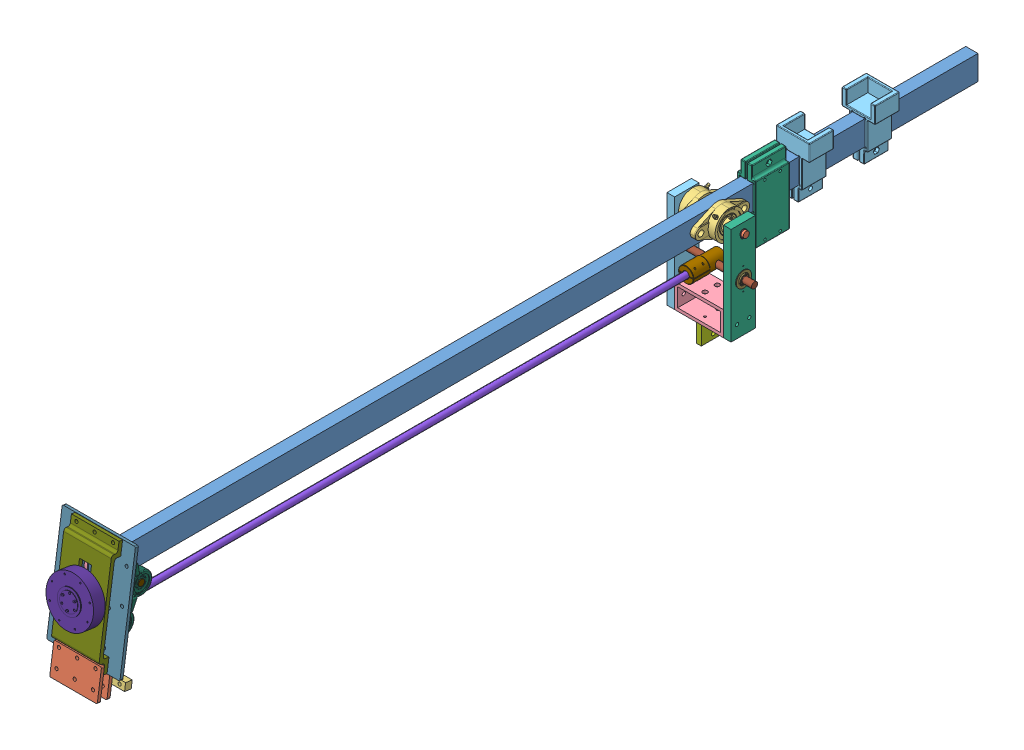
SolidWorks assembly BoomAssembly, configuration Unmovable Boom. Lengths in mm.
Overall size (166.47 305.68 1906.59).
39 component instances, 24 part files, 44 mates.
Components (placement in the parent):
- Boom-1: Boom [Default] at (0 158.75 -542.925) size (25.4 50.8 1828.8)
- Boom_Yoke Shaft-1: Boom_Yoke Shaft [Default] at (66.675 158.75 0) x (0 0 -1) z (1 0 0) size (12.7 12.7 130.18)
- UCFL201-8-TheTimkenCompany-3D-09-18-2023 (1).stp-1: UCFL201-8-TheTimkenCompany-3D-09-18-2023 (1).stp [Default] at (-12.7 158.75 0) x (0 0 1) z (0 1 0) size (113 33.3 60)
- UCFL201-8-TheTimkenCompany-3D-09-18-2023 (1).stp-2: UCFL201-8-TheTimkenCompany-3D-09-18-2023 (1).stp [Default] at (12.7 158.75 0) x (0 0 -1) z (0 1 0) size (113 33.3 60)
- Yoke-1: Yoke [Default] at origin size (133.35 241.3 50.8)
  - Yoke_Base-1: Yoke_Base [Default] x (0 0 -1) z (1 0 0) size (50.8 50.8 101.6)
  - Yoke-Prong-1: Yoke-Prong [Default] at (-50.8 0 0) x (0 0 1) z (-1 0 0) size (50.8 203.2 15.88)
  - Yoke_Prong_Encoder Side-1: Yoke_Prong_Encoder Side [Default] at (50.8 0 0) x (0 0 -1) z (1 0 0) size (50.8 203.2 15.88)
  - Yoke_Base Mount-1: Yoke_Base Mount [Default] at (0 -25.4 0) x (0 0 1) z (0 -1 0) size (50.8 9.53 38.1)
- 00_03_Boom_Assembly-1: 00_03_Boom_Assembly [Default] at (0 77.032 1256.8235) x (1 0 0) z (0 -0.000662 -1) size (160.07 31.75 1303.92)
  - 00_03_01_Boom-1: 00_03_01_Boom [Default] at origin size (12.7 12.7 1244.6)
  - 00_03_02_Boom_Shaft_End-1: 00_03_02_Boom_Shaft_End [3463N51] at (0 0 5.5563) size (31.71 31.75 69.85)
  - 00_03_02_Boom_Shaft_End-2: 00_03_02_Boom_Shaft_End [3463N51] at (0 0 1239.0438) x (-1 0 0) z (0 0 -1) size (31.71 31.75 69.85)
  - 00_03_03_92313A576_Super-Corrosion-Resistant Cup-Point Set Screw-1: 00_03_03_92313A576_Super-Corrosion-Resistant Cup-Point Set Screw [92313A576] at (0 0 -25.2586) x (-1 0 0) z (0 0 -1) size (8.13 8.07 10.1)
  - 00_03_03_92313A576_Super-Corrosion-Resistant Cup-Point Set Screw-2: 00_03_03_92313A576_Super-Corrosion-Resistant Cup-Point Set Screw [92313A576] at (0 0 1255.8886) size (8.13 8.07 10.1)
  - Rod-Yoke Shaft-1: Rod-Yoke Shaft [Default] at (0 0 1256.8238) size (160.07 12.7 12.7)
- 6383K234_Ball Bearing-1: 6383K234_Ball Bearing [6383K234] at (63.4365 76.2 0) x (0 0 1) z (-1 0 0) size (31.75 31.75 11.13)
- 6383K234_Ball Bearing-2: 6383K234_Ball Bearing [6383K234] at (-63.4365 76.2 0) x (0 0 -1) z (1 0 0) size (31.75 31.75 11.13)
- 90030A101_Heavy Duty External Retaining Ring-1: 90030A101_Heavy Duty External Retaining Ring [90030A101] at (67.425 158.75 0) x (0 0 -1) z (1 0 0) size (13.48 16.2 1.5)
- 90030A101_Heavy Duty External Retaining Ring-2: 90030A101_Heavy Duty External Retaining Ring [90030A101] at (70.5492 76.2 0) x (0 -0.10728 -0.994229) z (1 0 0) size (13.48 16.2 1.5) (hidden)
- Knuckle-1: Knuckle [Default] at (0 161.9092 1279.2741) x (0 0.142304 0.989823) z (-1 0 0) size (107.06 275.35 152.4)
  - Knuckle Plate^Knuckle-1: Knuckle Plate^Knuckle [Default] at origin size (6.35 228.6 152.4) (virtual)
  - 5913K61_Low-Profile Mounted Sealed Steel Ball Bearing-1: 5913K61_Low-Profile Mounted Sealed Steel Ball Bearing [5913K61] at (-22.2 0 -63.5) x (0 1 0) z (0 0 1) size (86.1 44.81 28.6)
  - 5913K61_Low-Profile Mounted Sealed Steel Ball Bearing-3: 5913K61_Low-Profile Mounted Sealed Steel Ball Bearing [5913K61] at (-22.2 0 63.5) x (0 -1 0) z (0 0 -1) size (86.1 44.81 28.6)
  - 5913K61_Low-Profile Mounted Sealed Steel Ball Bearing-4: 5913K61_Low-Profile Mounted Sealed Steel Ball Bearing [5913K61] at (-22.2 -82.55 -38.1) x (0 1 0) z (0 0 1) size (86.1 44.81 28.6)
  - 5913K61_Low-Profile Mounted Sealed Steel Ball Bearing-6: 5913K61_Low-Profile Mounted Sealed Steel Ball Bearing [5913K61] at (-22.2 -82.55 38.1) x (0 -1 0) z (0 0 -1) size (86.1 44.81 28.6)
  - 00_04_01_CANSide mount-1: 00_04_01_CANSide mount [Default] at (19.05 -127 0) x (-1 0 0) z (0 0 -1) size (20.32 227.33 99.06)
  - CE_AK80-6_Model-1: CE_AK80-6_Model [AliExpress (2.5mm)] at (26.67 -41.275 0) x (0 -1 0) z (0 0 1) size (98 40.5 98)
  - Boom_Knuckle Shaft-1: Boom_Knuckle Shaft [Default] at (-22.2 0 0) x (0 0 -1) z (1 0 0) size (142.17 12.7 12.7)
  - Rod_Knuckle Shaft-1: Rod_Knuckle Shaft [Default] at (-22.2 -82.55 0) x (0 0 -1) z (-1 0 0) size (94.55 12.7 12.7)
  - Bumper^Knuckle-1: Bumper^Knuckle [Default] at (0 -147.32 0) x (0 0 1) z (-1 0 0) size (99.06 62.94 6.35) (virtual)
  - Bumper^Knuckle-4: Bumper^Knuckle [Default] at (13.97 -147.32 0) x (0 0 -1) z (1 0 0) size (99.06 62.94 6.35) (virtual)
  - Part2^Knuckle-1: Part2^Knuckle [Default] at (-36.9201 -192.3946 0) x (0 0 -1) z (0 1 0) size (99.06 13.97 15.24) (virtual)
- 1870K3_Easy-Access Flange-Mounted Shaft Support-1: 1870K3_Easy-Access Flange-Mounted Shaft Support [1870K3] at (38.1 158.75 1257.3) x (0 -0.707107 -0.707107) z (0 0.707107 -0.707107) size (57.15 25.4 57.15)
- 1870K3_Easy-Access Flange-Mounted Shaft Support-2: 1870K3_Easy-Access Flange-Mounted Shaft Support [1870K3] at (-38.1 158.75 1257.3) x (0 0.707107 0.707107) z (0 0.707107 -0.707107) size (57.15 25.4 57.15)
- Battery Holder-1: Battery Holder [Default] at (0.127 184.15 -263.525) x (-1 0 0) z (0 0 -1) size (69.05 117.15 187.7)
  - Part1^Battery Holder adjustable-4: Part1^Battery Holder adjustable [Default] at (0 0 -93.85) size (69.05 117.15 50.8)
  - Part1^Battery Holder adjustable-3: Part1^Battery Holder adjustable [Default] at (0 0 93.85) x (-1 0 0) z (0 0 -1) size (69.05 117.15 50.8)
- PCB Holder-1: PCB Holder [Default] at (0 133.35 -144.3258) x (-1 0 0) z (0 0 1) size (38.35 146.05 71.16)
Mates (geometry in assembly coordinates):
- Concentric2: concentric anti-aligned: cylinder of Boom_Yoke Shaft-1 through (73.025 158.75 0) axis (-1 0 0) radius 6.35; cylinder of UCFL201-8-TheTimkenCompany-3D-09-18-2023 (1).stp-1 through (-30.5 158.75 0) axis (1 0 0) radius 6.35
- Concentric5: concentric aligned: cylinder of Boom_Yoke Shaft-1 through (73.025 158.75 0) axis (-1 0 0) radius 6.35; cylinder of UCFL201-8-TheTimkenCompany-3D-09-18-2023 (1).stp-2 through (30.5 158.75 0) axis (-1 0 0) radius 6.35
- Coincident7: coincident anti-aligned: plane of Boom-1 through (-12.7 133.35 1285.875) normal (-1 0 0); plane of UCFL201-8-TheTimkenCompany-3D-09-18-2023 (1).stp-1 through (-12.7 158.75 -0.033) normal (1 0 0)
- Coincident8: coincident anti-aligned: plane of Boom-1 through (12.7 133.35 1285.875) normal (1 0 0); plane of UCFL201-8-TheTimkenCompany-3D-09-18-2023 (1).stp-2 through (12.7 158.75 0.033) normal (-1 0 0)
- Coincident10: coincident aligned: plane of Boom-1 through (0 158.75 -542.925) normal (0 1 0); plane of UCFL201-8-TheTimkenCompany-3D-09-18-2023 (1).stp-1 through (-12.7 158.75 0) normal (0 1 0)
- Coincident11: coincident aligned: plane of Boom-1 through (0 158.75 -542.925) normal (0 1 0); plane of UCFL201-8-TheTimkenCompany-3D-09-18-2023 (1).stp-2 through (12.7 158.75 0) normal (0 1 0)
- Concentric6: concentric anti-aligned: cylinder of Yoke-1/Yoke-Prong-1 through (-66.675 76.2 0) axis (1 0 0) radius 6.35; cylinder of 00_03_Boom_Assembly-1/Rod-Yoke Shaft-1 through (69.7992 76.2 0) axis (-1 0 0) radius 6.35
- Coincident15: coincident anti-aligned: plane of Boom-1 through (0 158.75 -542.925) normal (1 0 0); plane of 00_03_Boom_Assembly-1/00_03_02_Boom_Shaft_End-2 through (0 76.2118 17.78) normal (-1 0 0)
- Coincident16: coincident anti-aligned: plane of Yoke-1/Yoke_Prong_Encoder Side-1 through (66.675 0 0) normal (1 0 0); plane of 6383K234_Ball Bearing-1 through (66.675 86.9188 0) normal (-1 0 0)
- Concentric7: concentric aligned: cylinder of 00_03_Boom_Assembly-1/Rod-Yoke Shaft-1 through (69.7992 76.2 0) axis (-1 0 0) radius 6.35; cylinder of 6383K234_Ball Bearing-1 through (58.674 76.2 0) axis (-1 0 0) radius 6.35
- Coincident17: coincident anti-aligned: plane of Yoke-1/Yoke-Prong-1 through (-66.675 0 0) normal (-1 0 0); plane of 6383K234_Ball Bearing-2 through (-66.675 86.9188 0) normal (1 0 0)
- Concentric8: concentric anti-aligned: cylinder of 00_03_Boom_Assembly-1/Rod-Yoke Shaft-1 through (69.7992 76.2 0) axis (-1 0 0) radius 6.35; cylinder of 6383K234_Ball Bearing-2 through (-58.674 76.2 0) axis (1 0 0) radius 6.35
- Coincident18: coincident anti-aligned: plane of 00_03_Boom_Assembly-1/Rod-Yoke Shaft-1 through (69.7992 76.2 0) normal (1 0 0); plane of 90030A101_Heavy Duty External Retaining Ring-2 through (69.7992 76.7579 -0.0602) normal (-1 0 0)
- Concentric9: concentric aligned: cylinder of 90030A101_Heavy Duty External Retaining Ring-2 through (71.2992 76.2 0) axis (-1 0 0) radius 5.5; cylinder of 00_03_Boom_Assembly-1/Rod-Yoke Shaft-1 through (90.2716 76.2 0) axis (-1 0 0) radius 6.35
- Coincident19: coincident anti-aligned: plane of Yoke-1/Yoke_Prong_Encoder Side-1 through (66.675 0 0) normal (1 0 0); plane of 90030A101_Heavy Duty External Retaining Ring-1 through (66.675 159.3111 0) normal (-1 0 0)
- Concentric10: concentric aligned: cylinder of Boom_Yoke Shaft-1 through (73.025 158.75 0) axis (-1 0 0) radius 6.35; cylinder of 90030A101_Heavy Duty External Retaining Ring-1 through (68.175 158.75 0) axis (-1 0 0) radius 5.5
- Concentric11: concentric anti-aligned: cylinder of Boom-1 through (12.7 158.75 1257.3) axis (1 0 0) radius 7.1437; cylinder of Knuckle-1/5913K61_Low-Profile Mounted Sealed Steel Ball Bearing-3 through (-63.5 158.75 1257.3) axis (-1 0 0) radius 6.35
- Concentric12: concentric aligned: cylinder of 00_03_Boom_Assembly-1/00_03_02_Boom_Shaft_End-1 through (15.875 77.0401 1269.0472) axis (-1 0 0) radius 6.35; cylinder of Knuckle-1/5913K61_Low-Profile Mounted Sealed Steel Ball Bearing-6 through (-38.1 77.0401 1269.0472) axis (-1 0 0) radius 6.35
- Coincident20: coincident anti-aligned: plane of Boom-1 through (0 158.75 -542.925) normal (1 0 0); plane of Knuckle-1/Knuckle Plate^Knuckle-1 through (0 161.9092 1279.2741) normal (-1 0 0)
- Coincident21: coincident anti-aligned: plane of Boom-1 through (12.7 133.35 1285.875) normal (1 0 0); plane of 1870K3_Easy-Access Flange-Mounted Shaft Support-1 through (12.7 164.3627 1262.9127) normal (-1 0 0)
- Parallel1: parallel aligned: plane of Boom-1 through (12.7 184.15 1285.875) normal (0 1 0)
- Coincident22: coincident anti-aligned: plane of Boom-1 through (-12.7 133.35 1285.875) normal (-1 0 0); plane of 1870K3_Easy-Access Flange-Mounted Shaft Support-2 through (-12.7 153.1373 1251.6873) normal (1 0 0)
- Parallel5: parallel aligned: plane of Boom-1 through (12.7 184.15 1285.875) normal (0 1 0)
- Concentric23: concentric aligned: cylinder of Boom-1 through (12.7 174.4654 1241.5846) axis (1 0 0) radius 2.3813; cylinder of 1870K3_Easy-Access Flange-Mounted Shaft Support-2 through (-16.6751 174.4654 1241.5846) axis (1 0 0) radius 2.2479
- Concentric26: concentric anti-aligned: cylinder of Boom-1 through (12.7 174.4654 1273.0154) axis (1 0 0) radius 2.3813; cylinder of 1870K3_Easy-Access Flange-Mounted Shaft Support-1 through (16.6751 174.4654 1273.0154) axis (-1 0 0) radius 2.2479
- Concentric29: concentric aligned: cylinder of Knuckle-1/Boom_Knuckle Shaft-1 through (90.6355 158.75 1257.3) axis (-1 0 0) radius 6.35; cylinder of 1870K3_Easy-Access Flange-Mounted Shaft Support-1 through (31.369 158.75 1257.3) axis (-1 0 0) radius 6.35
- Coincident23: coincident aligned: plane of Yoke-1 through (0 0 0) normal (0 0 1)
- Coincident24: coincident aligned: plane of Yoke-1 through (0 0 0) normal (0 1 0)
- Coincident25: coincident aligned: plane of Yoke-1 through (0 0 0) normal (1 0 0)
- Coincident26: coincident aligned: plane of Boom-1 through (0 158.75 -542.925) normal (1 0 0)
- Concentric42: concentric aligned: cylinder of Boom_Yoke Shaft-1 through (73.025 158.75 0) axis (-1 0 0) radius 6.35; cylinder of Yoke-1/Yoke_Prong_Encoder Side-1 through (66.675 158.75 0) axis (-1 0 0) radius 6.35
- Concentric43: concentric anti-aligned: cylinder of Boom-1 through (12.7 158.75 0) axis (1 0 0) radius 7.1437; cylinder of Boom_Yoke Shaft-1 through (73.025 158.75 0) axis (-1 0 0) radius 6.35
- Parallel6: parallel aligned: plane of Boom-1 through (12.7 184.15 1285.875) normal (0 1 0)
- Coincident27: coincident anti-aligned: plane of Boom-1 through (-12.7 133.35 1285.875) normal (-1 0 0); plane of Battery Holder-1/Part1^Battery Holder adjustable-4 through (-12.7 184.15 -220.475) normal (1 0 0)
- Coincident29: coincident anti-aligned: plane of Boom-1 through (12.7 184.15 1285.875) normal (0 1 0); plane of Battery Holder-1/Part1^Battery Holder adjustable-3 through (0.127 184.15 -306.575) normal (0 -1 0)
- Distance1: distance = 279.4 mm anti-aligned: plane of Battery Holder-1 through (0.127 184.15 -263.525) normal (0 0 -1); plane of Boom-1 through (0 158.75 -542.925) normal (0 0 1)
- Coincident30: coincident anti-aligned: plane of Boom_Yoke Shaft-1 through (-57.15 158.75 0) normal (-1 0 0); plane of Yoke-1/Yoke-Prong-1 through (-57.15 158.75 0) normal (1 0 0)
- Parallel7: parallel aligned: plane of Yoke-1 through (0 0 0) normal (0 1 0); plane of 6383K234_Ball Bearing-1 through (63.4365 76.2 0) normal (0 1 0)
- Parallel8: parallel aligned: plane of Yoke-1 through (0 0 0) normal (0 1 0); plane of 6383K234_Ball Bearing-2 through (-63.4365 76.2 0) normal (0 1 0)
- Parallel9: parallel aligned: plane of Boom_Yoke Shaft-1 through (66.675 158.75 0) normal (0 1 0); plane of Yoke-1 through (0 0 0) normal (0 1 0)
- Coincident34: coincident aligned: plane of Boom_Yoke Shaft-1 through (66.675 158.75 0) normal (0 1 0); plane of 90030A101_Heavy Duty External Retaining Ring-1 through (67.425 158.75 0) normal (0 1 0)
- Coincident35: coincident anti-aligned: plane of 00_03_Boom_Assembly-1/Rod-Yoke Shaft-1 through (0 76.2 0) normal (0 -1 0.000662); plane of 90030A101_Heavy Duty External Retaining Ring-2 through (70.5492 76.2 0) normal (0 1 -0.000662)
- Coincident36: coincident anti-aligned: plane of Boom-1 through (0 158.75 -542.925) normal (1 0 0); plane of PCB Holder-1 through (0 133.35 -144.3258) normal (-1 0 0)
- Coincident37: coincident aligned: plane of Boom-1 through (12.7 133.35 1285.875) normal (0 -1 0); plane of PCB Holder-1 through (0 133.35 -144.3258) normal (0 -1 0)
